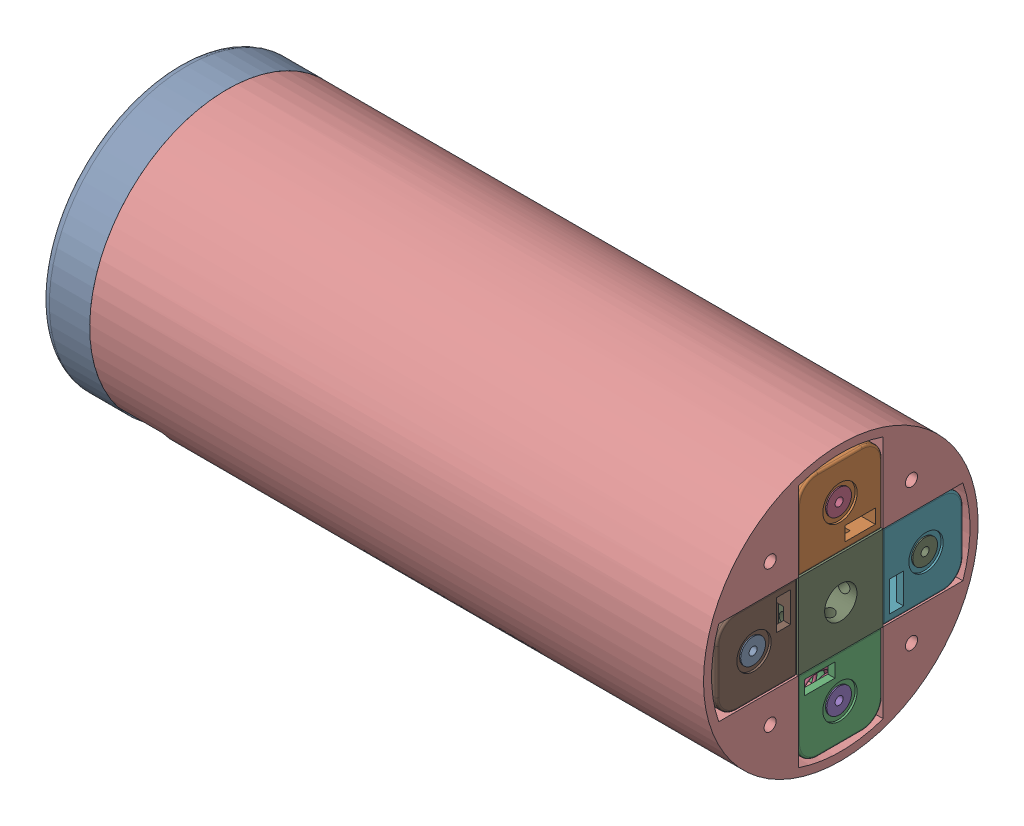
SolidWorks assembly Battery pack, configuration Default. Lengths in mm.
Overall size (164 68.02 68.02).
13 component instances, 6 part files, 17 mates.
Components (placement in the parent):
- 18650 battery single enclosure-1: 18650 battery single enclosure [Default] at (-38.777 -6.3563 24.7805) size (75.9 20 21.01)
- 18650 battery single enclosure-2: 18650 battery single enclosure [Default] at (-114.677 -6.3563 24.7805) size (75.9 20 21.01)
- Battery Pack Fillar-1: Battery Pack Fillar [Default] at (-152.627 -6.3563 35.2805) x (0 -1 0) z (0 0 1) size (21 152 21)
- 18650 battery single enclosure-3: 18650 battery single enclosure [Default] at (-38.777 -16.8563 35.2805) x (1 0 0) z (0 -1 0) size (75.9 20 21.01)
- 18650 battery single enclosure-4: 18650 battery single enclosure [Default] at (-38.777 -27.3563 24.7805) x (1 0 0) z (0 0 -1) size (75.9 20 21.01)
- 18650 battery single enclosure-5: 18650 battery single enclosure [Default] at (-38.777 -16.8563 14.2805) x (1 0 0) z (0 1 0) size (75.9 20 21.01)
- 18650 battery single enclosure-6: 18650 battery single enclosure [Default] at (-114.677 -16.8563 35.2805) x (1 0 0) z (0 -1 0) size (75.9 20 21.01)
- 18650 battery single enclosure-7: 18650 battery single enclosure [Default] at (-114.677 -27.3563 24.7805) x (1 0 0) z (0 0 -1) size (75.9 20 21.01)
- 18650 battery single enclosure-8: 18650 battery single enclosure [Default] at (-114.677 -16.8563 14.2805) x (1 0 0) z (0 1 0) size (75.9 20 21.01)
- Battery pack cover-1: Battery pack cover [Default] at (-0.627 -16.8563 24.7805) x (0 1 0) z (0 0 1) size (68 152 68)
- BMS-1: BMS [Default] at (-161.046 1.1437 42.7805) x (0 -1 0) z (0 0 1) size (36 4 36)
- DC socket-1: DC socket [Default] at (-147.127 -40.6499 48.5741) x (0 -0.707107 -0.707107) z (0 -0.707107 0.707107) size (9.4 15 14.3)
- Bottom cover-1: Bottom cover [Default] at (-164.627 -16.8563 24.7805) x (0 0.000297 -1) z (0 -1 -0.000297) size (68 12 68)
Mates (geometry in assembly coordinates):
- Coincident1: coincident anti-aligned: plane of 18650 battery single enclosure-1 through (-76.727 13.6437 35.2805) normal (-1 0 0); plane of 18650 battery single enclosure-2 through (-76.727 13.6437 35.2805) normal (1 0 0)
- Coincident2: coincident aligned: plane of 18650 battery single enclosure-1 through (-38.777 -6.3563 24.7805) normal (0 -1 0); plane of 18650 battery single enclosure-2 through (-114.677 -6.3563 24.7805) normal (0 -1 0)
- Coincident3: coincident aligned: plane of 18650 battery single enclosure-1 through (-0.827 13.6437 35.2805) normal (0 0 1); plane of 18650 battery single enclosure-2 through (-76.727 13.6437 35.2805) normal (0 0 1)
- Coincident4: coincident anti-aligned: plane of 18650 battery single enclosure-2 through (-114.677 -6.3563 24.7805) normal (0 -1 0); plane of Battery Pack Fillar-1 through (-0.627 -6.3563 35.2805) normal (0 1 0)
- Coincident5: coincident aligned: plane of 18650 battery single enclosure-2 through (-152.627 13.6437 35.2805) normal (-1 0 0); plane of Battery Pack Fillar-1 through (-152.627 -6.3563 35.2805) normal (-1 0 0)
- Coincident6: coincident aligned: plane of 18650 battery single enclosure-2 through (-76.727 13.6437 14.2805) normal (0 0 -1); plane of Battery Pack Fillar-1 through (-0.627 -6.3563 14.2805) normal (0 0 -1)
- Coincident7: coincident anti-aligned: plane of 18650 battery single enclosure-3 through (-0.827 -27.3563 55.2805) normal (0 -1 0); plane of Battery pack cover-1 through (-152.627 -27.3563 35.2805) normal (0 1 0)
- Coincident8: coincident anti-aligned: plane of 18650 battery single enclosure-4 through (-0.827 -47.3563 35.2805) normal (0 0 1); plane of Battery pack cover-1 through (-152.627 -27.3563 35.2805) normal (0 0 -1)
- Coincident9: coincident aligned: plane of Battery Pack Fillar-1 through (-152.627 -6.3563 35.2805) normal (-1 0 0); plane of Battery pack cover-1 through (-152.627 -16.8563 24.7805) normal (-1 0 0)
- Width1: width aligned: plane of BMS-1 through (-157.046 -34.8563 42.7805) normal (0 -1 0); plane of Battery Pack Fillar-1 through (-157.046 1.1437 42.7805) normal (0 1 0); plane of BMS-1 through (-0.627 -27.3563 35.2805) normal (0 -1 0); plane of Battery Pack Fillar-1 through (-0.627 -6.3563 35.2805) normal (0 1 0)
- Width2: width anti-aligned: plane of BMS-1 through (-157.046 1.1437 6.7805) normal (0 0 -1); plane of Battery Pack Fillar-1 through (-157.046 1.1437 42.7805) normal (0 0 1); plane of BMS-1 through (-0.627 -6.3563 35.2805) normal (0 0 1); plane of Battery Pack Fillar-1 through (-0.627 -6.3563 14.2805) normal (0 0 -1)
- Coincident10: coincident anti-aligned: plane of Battery pack cover-1 through (-141.627 17.1447 -9.2205) normal (-1 0 0); plane of DC socket-1 through (-141.627 -35.1345 49.4226) normal (1 0 0)
- Coincident11: coincident anti-aligned: plane of Battery pack cover-1 through (-0.627 13.9627 -12.4025) normal (0 0.707107 0.707107); plane of DC socket-1 through (-141.627 -41.4985 43.0586) normal (0 -0.707107 -0.707107)
- Coincident12: coincident: line of Battery pack cover-1 through (-152.627 -27.3563 41.6444) axis (1 0 0); plane of DC socket-1 through (-146.127 -30.5383 38.4624) normal (0 0.707107 -0.707107)
- Concentric1: concentric anti-aligned: cylinder of Battery pack cover-1 through (-152.627 -16.8563 24.7805) axis (1 0 0) radius 34; cylinder of Bottom cover-1 through (-161.627 -16.8563 24.7805) axis (-1 0 0) radius 34
- Concentric5: concentric: cylinder of Battery pack cover-1 through (-149.627 -37.3563 4.2805) axis (-1 0 0) radius 3; cylinder of Bottom cover-1 through (-155.627 -37.3624 4.2744) axis (1 0 0) radius 3
- Coincident13: coincident anti-aligned: plane of Battery pack cover-1 through (-152.627 -16.8563 24.7805) normal (-1 0 0); plane of Bottom cover-1 through (-152.627 -16.8563 24.7805) normal (1 0 0)
